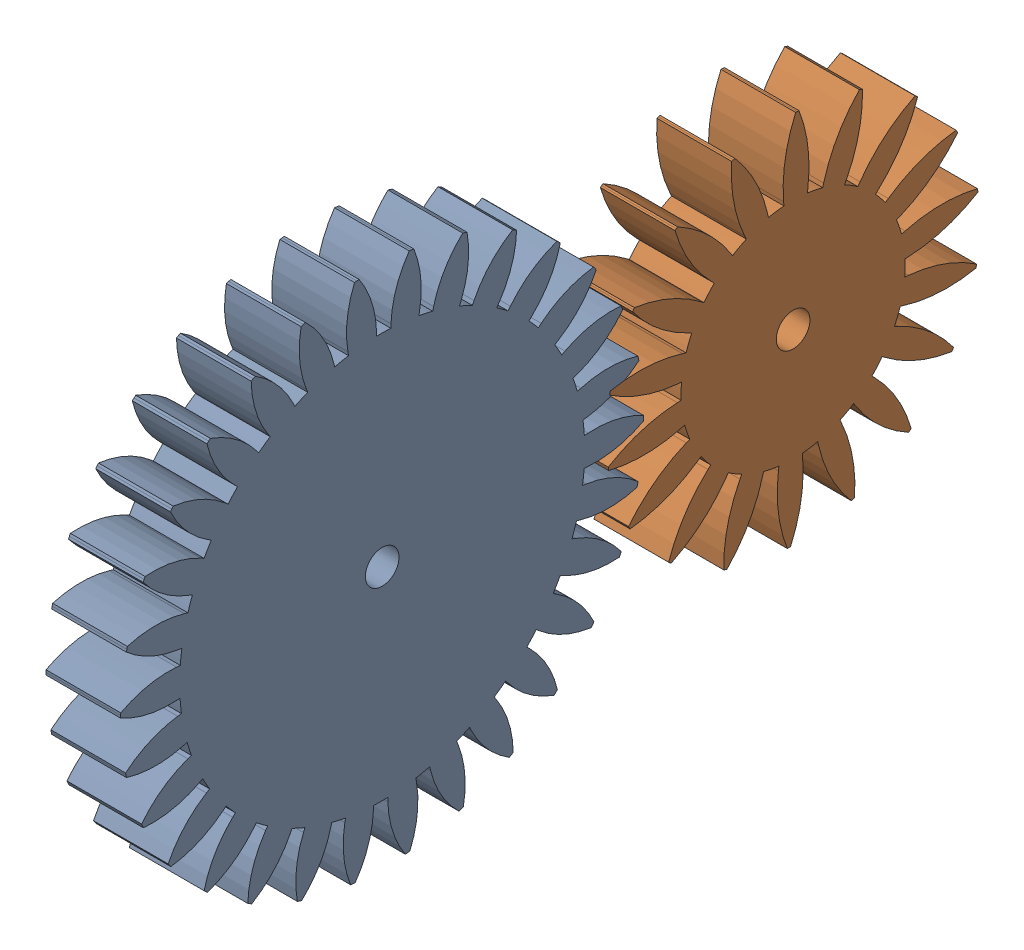
SolidWorks assembly Gear Testing, configuration Default. Lengths in mm.
Overall size (10 96.2 186).
2 component instances, 2 part files, 5 mates.
Components (placement in the parent):
- Middle Gear v01-1: Middle Gear v01 [Default] at (-31.6878 26.1429 111.5957) x (1 0 0) z (0 -0.523519 0.852014) size (10 69.98 69.87)
- Motor Gear v01-2: Motor Gear v01 [Default] at (-31.6878 26.1429 56.5957) x (1 0 0) z (0 -0.991905 0.126981) size (10 49.91 49.77)
Mates (geometry in assembly coordinates):
- Concentric14: concentric aligned: circle of Middle Gear v01-1
- Concentric15: concentric aligned: circle of Motor Gear v01-2
- Coincident7: coincident aligned: plane of Motor Gear v01-2 through (-21.6878 26.1429 56.5957) normal (1 0 0)
- GearMate1: gear = 0.257 : 0.429 mm: cylinder of Middle Gear v01-1 through (-21.6878 26.1429 111.5957) axis (-1 0 0) radius 2.25; cylinder of Motor Gear v01-2 through (-21.6878 26.1429 56.5957) axis (-1 0 0) radius 2.25
- Coincident8: coincident aligned: plane of Middle Gear v01-1 through (-21.6878 26.1429 111.5957) normal (1 0 0); plane of Motor Gear v01-2 through (-21.6878 26.1429 56.5957) normal (1 0 0)
